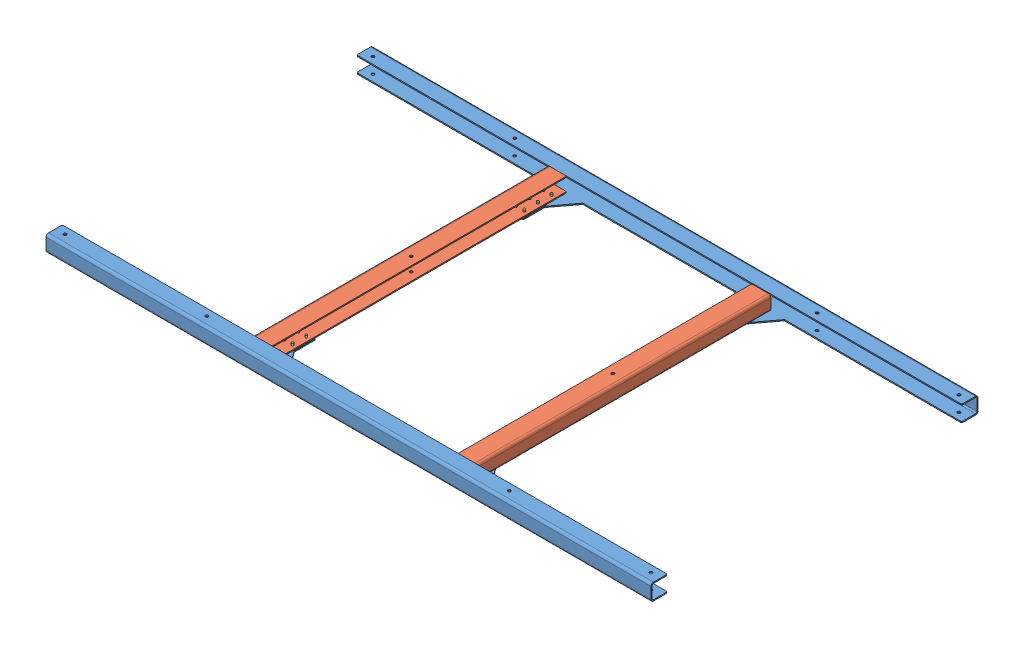
SolidWorks assembly GE-20102, configuration Default. Lengths in mm.
Overall size (1409.7 39.7 762).
28 component instances, 3 part files, 57 mates.
Components (placement in the parent):
- GE-20102-01-1: GE-20102-01 [Default] at (0 0.9889 762) size (1409.7 38.1 139.7)
- GE-20102-01-2: GE-20102-01 [Default] at (1409.7 0.9889 0) x (-1 0 0) z (0 0 -1) size (1409.7 38.1 139.7)
- GE-20102-02-1: GE-20102-02 [Default] at (447.1568 8.3752 723.9) x (0 0 -1) z (0 -1 0) size (685.8 44.45 33.89)
- GE-20102-02-2: GE-20102-02 [Default] at (962.5432 6.8208 38.1) x (0 0 1) z (0 -1 0) size (685.8 44.45 33.89)
- rivet_.1875_.126-.25-28: rivet_.1875_.126-.25 [Default] at (930.275 -1.6679 698.5) x (1 0 0) z (0 -1 0) size (10.01 10.01 13.03)
- rivet_.1875_.126-.25-16: rivet_.1875_.126-.25 [Default] at (949.325 -1.6679 698.5) x (1 0 0) z (0 -1 0) size (10.01 10.01 13.03)
- rivet_.1875_.126-.25-23: rivet_.1875_.126-.25 [Default] at (949.325 -1.6679 666.75) x (1 0 0) z (0 -1 0) size (10.01 10.01 13.03)
- rivet_.1875_.126-.25-24: rivet_.1875_.126-.25 [Default] at (930.275 -1.6679 666.75) x (1 0 0) z (0 -1 0) size (10.01 10.01 13.03)
- rivet_.1875_.126-.25-25: rivet_.1875_.126-.25 [Default] at (949.325 -1.6679 635) x (1 0 0) z (0 -1 0) size (10.01 10.01 13.03)
- rivet_.1875_.126-.25-26: rivet_.1875_.126-.25 [Default] at (930.275 -1.6679 635) x (-0.837169 0 -0.546944) z (0 -1 0) size (10.01 10.01 13.03)
- rivet_.1875_.126-.25-27: rivet_.1875_.126-.25 [Default] at (460.375 -1.6679 666.75) x (1 0 0) z (0 -1 0) size (10.01 10.01 13.03)
- rivet_.1875_.126-.25-40: rivet_.1875_.126-.25 [Default] at (479.425 -1.6679 698.5) x (1 0 0) z (0 -1 0) size (10.01 10.01 13.03)
- rivet_.1875_.126-.25-39: rivet_.1875_.126-.25 [Default] at (479.425 -1.6679 666.75) x (1 0 0) z (0 -1 0) size (10.01 10.01 13.03)
- rivet_.1875_.126-.25-43: rivet_.1875_.126-.25 [Default] at (460.375 -1.6679 635) x (1 0 0) z (0 -1 0) size (10.01 10.01 13.03)
- rivet_.1875_.126-.25-46: rivet_.1875_.126-.25 [Default] at (479.425 -1.6679 635) x (1 0 0) z (0 -1 0) size (10.01 10.01 13.03)
- rivet_.1875_.126-.25-44: rivet_.1875_.126-.25 [Default] at (460.375 -1.6679 698.5) x (-0.837169 0 -0.546944) z (0 -1 0) size (10.01 10.01 13.03)
- rivet_.1875_.126-.25-45: rivet_.1875_.126-.25 [Default] at (479.425 -1.6679 127) x (1 0 0) z (0 -1 0) size (10.01 10.01 13.03)
- rivet_.1875_.126-.25-34: rivet_.1875_.126-.25 [Default] at (460.375 -1.6679 127) x (1 0 0) z (0 -1 0) size (10.01 10.01 13.03)
- rivet_.1875_.126-.25-48: rivet_.1875_.126-.25 [Default] at (479.425 -1.6679 63.5) x (1 0 0) z (0 -1 0) size (10.01 10.01 13.03)
- rivet_.1875_.126-.25-41: rivet_.1875_.126-.25 [Default] at (460.375 -1.6679 95.25) x (1 0 0) z (0 -1 0) size (10.01 10.01 13.03)
- rivet_.1875_.126-.25-42: rivet_.1875_.126-.25 [Default] at (460.375 -1.6679 63.5) x (1 0 0) z (0 -1 0) size (10.01 10.01 13.03)
- rivet_.1875_.126-.25-38: rivet_.1875_.126-.25 [Default] at (479.425 -1.6679 95.25) x (1 0 0) z (0 -1 0) size (10.01 10.01 13.03)
- rivet_.1875_.126-.25-47: rivet_.1875_.126-.25 [Default] at (949.325 -1.6679 127) x (1 0 0) z (0 -1 0) size (10.01 10.01 13.03)
- rivet_.1875_.126-.25-50: rivet_.1875_.126-.25 [Default] at (930.275 -1.6679 127) x (1 0 0) z (0 -1 0) size (10.01 10.01 13.03)
- rivet_.1875_.126-.25-52: rivet_.1875_.126-.25 [Default] at (949.325 -1.6679 95.25) x (1 0 0) z (0 -1 0) size (10.01 10.01 13.03)
- rivet_.1875_.126-.25-51: rivet_.1875_.126-.25 [Default] at (930.275 -1.6679 95.25) x (1 0 0) z (0 -1 0) size (10.01 10.01 13.03)
- rivet_.1875_.126-.25-49: rivet_.1875_.126-.25 [Default] at (949.325 -1.6679 63.5) x (1 0 0) z (0 -1 0) size (10.01 10.01 13.03)
- rivet_.1875_.126-.25-53: rivet_.1875_.126-.25 [Default] at (930.275 -1.6679 63.5) x (1 0 0) z (0 -1 0) size (10.01 10.01 13.03)
Mates (geometry in assembly coordinates):
- Coincident29: coincident aligned: plane of GE-20102-01-1 through (0 36.4321 762) normal (0 1 0); plane of GE-20102-01-2 through (1409.7 36.4321 0) normal (0 1 0)
- Distance3: distance = 762 mm anti-aligned: plane of GE-20102-01-1 through (0 0.9889 762) normal (0 0 1); plane of GE-20102-01-2 through (1409.7 0.9889 0) normal (0 0 -1)
- Coincident31: coincident aligned: plane of GE-20102-01-1 through (0 -1.6679 762) normal (-1 0 0); plane of GE-20102-01-2 through (0 -1.6679 0) normal (-1 0 0)
- Coincident32: coincident aligned: plane of GE-20102-01-1 through (0 36.4321 762) normal (0 1 0); plane of GE-20102-02-1 through (447.1568 36.4321 723.9) normal (0 1 0)
- Coincident33: coincident anti-aligned: plane of GE-20102-01-2 through (0 36.4321 38.1) normal (0 0 1); plane of GE-20102-02-1 through (447.1568 36.4321 38.1) normal (0 0 -1)
- Coincident34: coincident aligned: plane of GE-20102-01-2 through (488.95 -1.6679 88.9) normal (1 0 0); plane of GE-20102-02-1 through (488.95 2.5434 723.9) normal (1 0 0)
- Coincident35: coincident anti-aligned: plane of GE-20102-01-1 through (0 0.9889 762) normal (0 1 0); plane of GE-20102-02-2 through (962.5432 0.9889 38.1) normal (0 -1 0)
- Concentric1: concentric anti-aligned: circle of GE-20102-01-2; circle of GE-20102-02-2
- Concentric2: concentric aligned: cylinder of GE-20102-01-2 through (930.275 -1.6679 63.5) axis (0 -1 0) radius 2.4574; cylinder of GE-20102-02-2 through (930.275 0.9889 63.5) axis (0 -1 0) radius 2.4574
- Coincident36: coincident anti-aligned: plane of GE-20102-01-1 through (0 -1.6679 762) normal (0 -1 0); plane of rivet_.1875_.126-.25-28 through (930.275 -1.6679 698.5) normal (0 1 0)
- Coincident37: coincident anti-aligned: plane of GE-20102-01-1 through (0 -1.6679 762) normal (0 -1 0); plane of rivet_.1875_.126-.25-23 through (949.325 -1.6679 666.75) normal (0 1 0)
- Coincident38: coincident anti-aligned: plane of GE-20102-01-1 through (0 -1.6679 762) normal (0 -1 0); plane of rivet_.1875_.126-.25-25 through (949.325 -1.6679 635) normal (0 1 0)
- Coincident39: coincident anti-aligned: plane of GE-20102-01-1 through (0 -1.6679 762) normal (0 -1 0); plane of rivet_.1875_.126-.25-28 through (930.275 -1.6679 698.5) normal (0 1 0)
- Coincident40: coincident anti-aligned: plane of GE-20102-01-1 through (0 -1.6679 762) normal (0 -1 0); plane of rivet_.1875_.126-.25-24 through (930.275 -1.6679 666.75) normal (0 1 0)
- Coincident41: coincident anti-aligned: plane of GE-20102-01-1 through (0 -1.6679 762) normal (0 -1 0); plane of rivet_.1875_.126-.25-26 through (930.275 -1.6679 635) normal (0 1 0)
- Coincident42: coincident anti-aligned: plane of GE-20102-01-1 through (0 -1.6679 762) normal (0 -1 0); plane of rivet_.1875_.126-.25-40 through (479.425 -1.6679 698.5) normal (0 1 0)
- Coincident43: coincident anti-aligned: plane of GE-20102-01-1 through (0 -1.6679 762) normal (0 -1 0); plane of rivet_.1875_.126-.25-39 through (479.425 -1.6679 666.75) normal (0 1 0)
- Coincident44: coincident anti-aligned: plane of GE-20102-01-1 through (0 -1.6679 762) normal (0 -1 0); plane of rivet_.1875_.126-.25-46 through (479.425 -1.6679 635) normal (0 1 0)
- Coincident45: coincident anti-aligned: plane of GE-20102-01-1 through (0 -1.6679 762) normal (0 -1 0); plane of rivet_.1875_.126-.25-27 through (460.375 -1.6679 666.75) normal (0 1 0)
- Coincident46: coincident anti-aligned: plane of GE-20102-01-1 through (0 -1.6679 762) normal (0 -1 0); plane of rivet_.1875_.126-.25-43 through (460.375 -1.6679 635) normal (0 1 0)
- Coincident47: coincident anti-aligned: plane of GE-20102-01-1 through (0 -1.6679 762) normal (0 -1 0); plane of rivet_.1875_.126-.25-44 through (460.375 -1.6679 698.5) normal (0 1 0)
- Coincident48: coincident anti-aligned: plane of GE-20102-01-2 through (1409.7 -1.6679 0) normal (0 -1 0); plane of rivet_.1875_.126-.25-48 through (479.425 -1.6679 63.5) normal (0 1 0)
- Coincident49: coincident anti-aligned: plane of GE-20102-01-2 through (1409.7 -1.6679 0) normal (0 -1 0); plane of rivet_.1875_.126-.25-45 through (479.425 -1.6679 127) normal (0 1 0)
- Coincident50: coincident anti-aligned: plane of GE-20102-01-2 through (1409.7 -1.6679 0) normal (0 -1 0); plane of rivet_.1875_.126-.25-42 through (460.375 -1.6679 63.5) normal (0 1 0)
- Coincident51: coincident anti-aligned: plane of GE-20102-01-2 through (1409.7 -1.6679 0) normal (0 -1 0); plane of rivet_.1875_.126-.25-41 through (460.375 -1.6679 95.25) normal (0 1 0)
- Coincident52: coincident anti-aligned: plane of GE-20102-01-2 through (1409.7 -1.6679 0) normal (0 -1 0); plane of rivet_.1875_.126-.25-34 through (460.375 -1.6679 127) normal (0 1 0)
- Coincident53: coincident anti-aligned: plane of GE-20102-01-2 through (1409.7 -1.6679 0) normal (0 -1 0); plane of rivet_.1875_.126-.25-38 through (479.425 -1.6679 95.25) normal (0 1 0)
- Coincident54: coincident anti-aligned: plane of GE-20102-01-2 through (1409.7 -1.6679 0) normal (0 -1 0); plane of rivet_.1875_.126-.25-47 through (949.325 -1.6679 127) normal (0 1 0)
- Coincident55: coincident anti-aligned: plane of GE-20102-01-2 through (1409.7 -1.6679 0) normal (0 -1 0); plane of rivet_.1875_.126-.25-52 through (949.325 -1.6679 95.25) normal (0 1 0)
- Coincident56: coincident anti-aligned: plane of GE-20102-01-2 through (1409.7 -1.6679 0) normal (0 -1 0); plane of rivet_.1875_.126-.25-49 through (949.325 -1.6679 63.5) normal (0 1 0)
- Coincident57: coincident anti-aligned: plane of GE-20102-01-2 through (1409.7 -1.6679 0) normal (0 -1 0); plane of rivet_.1875_.126-.25-50 through (930.275 -1.6679 127) normal (0 1 0)
- Coincident58: coincident anti-aligned: plane of GE-20102-01-2 through (1409.7 -1.6679 0) normal (0 -1 0); plane of rivet_.1875_.126-.25-51 through (930.275 -1.6679 95.25) normal (0 1 0)
- Coincident59: coincident anti-aligned: plane of GE-20102-01-2 through (1409.7 -1.6679 0) normal (0 -1 0); plane of rivet_.1875_.126-.25-53 through (930.275 -1.6679 63.5) normal (0 1 0)
- Concentric3: concentric aligned: cylinder of GE-20102-01-2 through (949.325 -1.6679 127) axis (0 -1 0) radius 2.4574; cylinder of rivet_.1875_.126-.25-47 through (949.325 9.7621 127) axis (0 -1 0) radius 2.3813
- Concentric4: concentric aligned: cylinder of GE-20102-01-2 through (949.325 -1.6679 95.25) axis (0 -1 0) radius 2.4574; cylinder of rivet_.1875_.126-.25-52 through (949.325 9.7621 95.25) axis (0 -1 0) radius 2.3813
- Concentric5: concentric aligned: cylinder of GE-20102-01-2 through (930.275 -1.6679 127) axis (0 -1 0) radius 2.4574; cylinder of rivet_.1875_.126-.25-50 through (930.275 9.7621 127) axis (0 -1 0) radius 2.3813
- Concentric6: concentric aligned: cylinder of GE-20102-01-2 through (930.275 -1.6679 95.25) axis (0 -1 0) radius 2.4574; cylinder of rivet_.1875_.126-.25-51 through (930.275 9.7621 95.25) axis (0 -1 0) radius 2.3813
- Concentric7: concentric aligned: cylinder of GE-20102-01-2 through (949.325 -1.6679 63.5) axis (0 -1 0) radius 2.4574; cylinder of rivet_.1875_.126-.25-49 through (949.325 9.7621 63.5) axis (0 -1 0) radius 2.3813
- Concentric8: concentric aligned: circle of GE-20102-01-2; cylinder of rivet_.1875_.126-.25-53 through (930.275 9.7621 63.5) axis (0 -1 0) radius 2.3813
- Concentric9: concentric aligned: cylinder of GE-20102-01-1 through (479.425 -1.6679 635) axis (0 -1 0) radius 2.4574; cylinder of rivet_.1875_.126-.25-46 through (479.425 9.7621 635) axis (0 -1 0) radius 2.3813
- Concentric10: concentric aligned: cylinder of GE-20102-01-1 through (460.375 -1.6679 666.75) axis (0 -1 0) radius 2.4574; cylinder of rivet_.1875_.126-.25-27 through (460.375 9.7621 666.75) axis (0 -1 0) radius 2.3813
- Concentric11: concentric aligned: cylinder of GE-20102-01-1 through (460.375 -1.6679 635) axis (0 -1 0) radius 2.4574; cylinder of rivet_.1875_.126-.25-43 through (460.375 9.7621 635) axis (0 -1 0) radius 2.3813
- Concentric12: concentric aligned: circle of GE-20102-01-1; cylinder of rivet_.1875_.126-.25-44 through (460.375 9.7621 698.5) axis (0 -1 0) radius 2.3813
- Concentric13: concentric aligned: circle of GE-20102-01-1; cylinder of rivet_.1875_.126-.25-39 through (479.425 9.7621 666.75) axis (0 -1 0) radius 2.3813
- Concentric14: concentric aligned: circle of GE-20102-01-1; cylinder of rivet_.1875_.126-.25-40 through (479.425 9.7621 698.5) axis (0 -1 0) radius 2.3813
- Concentric15: concentric aligned: circle of GE-20102-01-1; cylinder of rivet_.1875_.126-.25-16 through (949.325 9.7621 698.5) axis (0 -1 0) radius 2.3813
- Concentric16: concentric aligned: cylinder of GE-20102-01-1 through (930.275 -1.6679 698.5) axis (0 -1 0) radius 2.4574; cylinder of rivet_.1875_.126-.25-28 through (930.275 9.7621 698.5) axis (0 -1 0) radius 2.3813
- Concentric17: concentric aligned: circle of GE-20102-01-1; cylinder of rivet_.1875_.126-.25-23 through (949.325 9.7621 666.75) axis (0 -1 0) radius 2.3813
- Concentric18: concentric aligned: cylinder of GE-20102-01-1 through (930.275 -1.6679 666.75) axis (0 -1 0) radius 2.4574; cylinder of rivet_.1875_.126-.25-24 through (930.275 9.7621 666.75) axis (0 -1 0) radius 2.3813
- Concentric19: concentric aligned: cylinder of GE-20102-01-1 through (949.325 -1.6679 635) axis (0 -1 0) radius 2.4574; cylinder of rivet_.1875_.126-.25-25 through (949.325 9.7621 635) axis (0 -1 0) radius 2.3813
- Concentric20: concentric aligned: circle of GE-20102-01-1; cylinder of rivet_.1875_.126-.25-26 through (930.275 9.7621 635) axis (0 -1 0) radius 2.3813
- Concentric21: concentric aligned: circle of GE-20102-01-2; cylinder of rivet_.1875_.126-.25-48 through (479.425 9.7621 63.5) axis (0 -1 0) radius 2.3813
- Concentric22: concentric aligned: circle of GE-20102-01-2; cylinder of rivet_.1875_.126-.25-42 through (460.375 9.7621 63.5) axis (0 -1 0) radius 2.3813
- Concentric23: concentric aligned: circle of GE-20102-01-2; cylinder of rivet_.1875_.126-.25-38 through (479.425 9.7621 95.25) axis (0 -1 0) radius 2.3813
- Concentric24: concentric aligned: cylinder of GE-20102-01-2 through (460.375 -1.6679 95.25) axis (0 -1 0) radius 2.4574; cylinder of rivet_.1875_.126-.25-41 through (460.375 9.7621 95.25) axis (0 -1 0) radius 2.3813
- Concentric25: concentric aligned: circle of GE-20102-01-2; cylinder of rivet_.1875_.126-.25-34 through (460.375 9.7621 127) axis (0 -1 0) radius 2.3813
- Concentric26: concentric aligned: cylinder of GE-20102-01-2 through (479.425 -1.6679 127) axis (0 -1 0) radius 2.4574; cylinder of rivet_.1875_.126-.25-45 through (479.425 9.7621 127) axis (0 -1 0) radius 2.3813
